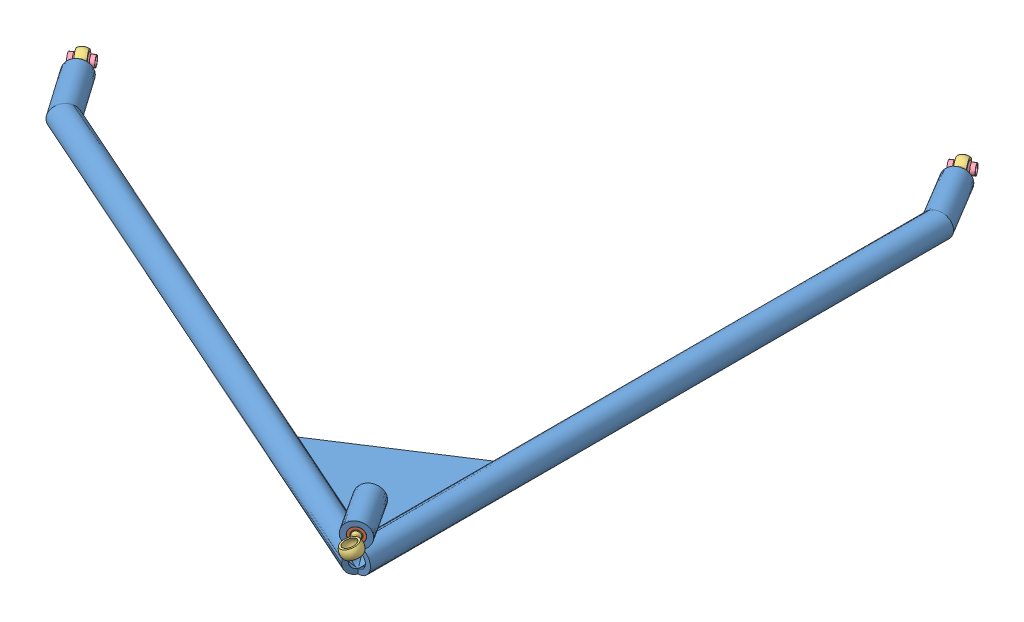
SolidWorks assembly wishbone assembly, configuration Default. Lengths in mm.
Overall size (386.38 31.4 434.57).
12 component instances, 4 part files, 9 mates.
Components (placement in the parent):
- wishbone rod new-1: wishbone rod new [Default<As Machined>] at (-31.4637 -2.1858 -143.5628) size (370.16 31.4 408.25)
- rod end screw cap assembly-1: rod end screw cap assembly [Default] at (25.3979 43.1564 111.0109) x (0.791187 0.331707 -0.513803) z (0.544639 0 0.838671) size (12 9.2 41.45)
  - rod end screw cap-1: rod end screw cap [Default] at (-112.4655 8.0145 66.4016) size (9.2 9.2 25)
  - Pushrod screw-1: Pushrod screw [Default] at (-112.4655 8.0145 76.856) x (0 0 -1) z (1 0 0) size (36.45 6 12)
- rod end screw cap assembly-2: rod end screw cap assembly [Default] at (-8.5789 -114.6513 -121.0371) x (0 -1 0) z (-0.515038 0 -0.857167) size (12 9.2 41.45)
  - rod end screw cap-1: rod end screw cap [Default] at (-112.4655 8.0145 66.4016) size (9.2 9.2 25)
  - Pushrod screw-1: Pushrod screw [Default] at (-112.4655 8.0145 76.856) x (0 0 -1) z (1 0 0) size (36.45 6 12)
- rod end screw cap assembly-3: rod end screw cap assembly [Default] at (-355.1906 110.2798 104.0552) x (0 1 0) z (-0.573576 0 -0.819152) size (12 9.2 41.45)
  - rod end screw cap-1: rod end screw cap [Default] at (-112.4655 8.0145 66.4016) size (9.2 9.2 25)
  - Pushrod screw-1: Pushrod screw [Default] at (-112.4655 8.0145 76.856) x (0 0 -1) z (1 0 0) size (36.45 6 12)
- J1-1: J1 [Default] at (-49.6059 -2.1858 -186.3117) x (-0.541557 0.106231 -0.833925) z (0.057857 0.994342 0.089092) size (10 12.94 10)
- J1-2: J1 [Default] at (-387.2818 -2.1858 32.9775) x (-0.543385 0.067829 -0.836739) z (0.036942 0.997697 0.056886) size (10 12.94 10)
Mates (geometry in assembly coordinates):
- Coincident4: coincident anti-aligned: axis of wishbone rod new-1 through (-45.9873 13.4115 200.7729) axis (0.544639 0 0.838671); line of rod end screw cap assembly-1/Pushrod screw-1 through (-23.9542 13.4115 234.7007) axis (-0.544639 0 -0.838671)
- Coincident6: coincident aligned: plane of wishbone rod new-1 through (-29.6481 13.4115 225.933) normal (0.544639 0 0.838671); plane of rod end screw cap assembly-1/rod end screw cap-1 through (-29.6481 13.4115 225.933) normal (0.544639 0 0.838671)
- Coincident7: coincident aligned: axis of wishbone rod new-1 through (-49.648 -2.1858 -173.8266) axis (0.515038 0 0.857167); line of rod end screw cap assembly-2/Pushrod screw-1 through (-55.0324 -2.1858 -182.7877) axis (0.515038 0 0.857167)
- Coincident8: coincident aligned: plane of wishbone rod new-1 through (-49.648 -2.1858 -173.8266) normal (-0.515038 0 -0.857167); plane of rod end screw cap assembly-2/rod end screw cap-1 through (-49.648 -2.1858 -173.8266) normal (-0.515038 0 -0.857167)
- Coincident9: coincident aligned: axis of wishbone rod new-1 through (-386.7119 -2.1858 45.0653) axis (0.573576 0 0.819152); line of rod end screw cap assembly-3/Pushrod screw-1 through (-392.7083 -2.1858 36.5015) axis (0.573576 0 0.819152)
- Coincident11: coincident aligned: plane of wishbone rod new-1 through (-386.7119 -2.1858 45.0653) normal (-0.573576 0 -0.819152); plane of rod end screw cap assembly-3/rod end screw cap-1 through (-386.7119 -2.1858 45.0653) normal (-0.573576 0 -0.819152)
- Concentric2: concentric: sphere of rod end screw cap assembly-2/Pushrod screw-1; sphere of J1-1
- Concentric3: concentric: sphere of rod end screw cap assembly-3/Pushrod screw-1; sphere of J1-2
- Coincident12: coincident aligned: axis of J1-1 through (-60.4589 -2.1858 -179.2637) axis (0.838671 0 -0.544639); axis of J1-2 through (-398.1348 -2.1858 40.0255) axis (0.838671 0 -0.544639)
